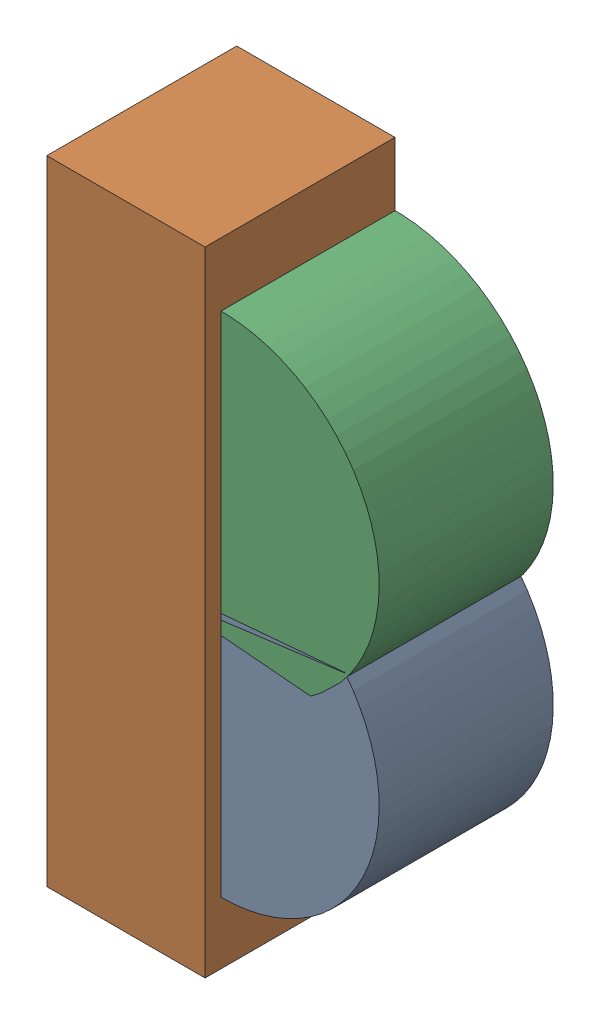
SolidWorks assembly D15, configuration Default. Lengths in mm.
Overall size (1 2 0.6).
6 component instances, 2 part files, 0 mates.
Components (placement in the parent):
- 786389736-1: 786389736 [Default] at (139 33.0461 0) x (0 1 0) z (0 0 1) size (1 1 0.55)
  - Cylinder-1: Cylinder [Default] at origin size (1 1 0.55)
- 836753648-1: 836753648 [Default] at (138.75 33.35 0) size (0.5 2 0.6)
  - Extruded_33-1: Extruded_33 [Default] at origin size (0.5 2 0.6)
- 786389736-2: 786389736 [Default] at (139 33.65 0) x (0 1 0) z (0 0 1) size (1 1 0.55)
  - Cylinder-1: Cylinder [Default] at origin size (1 1 0.55)
